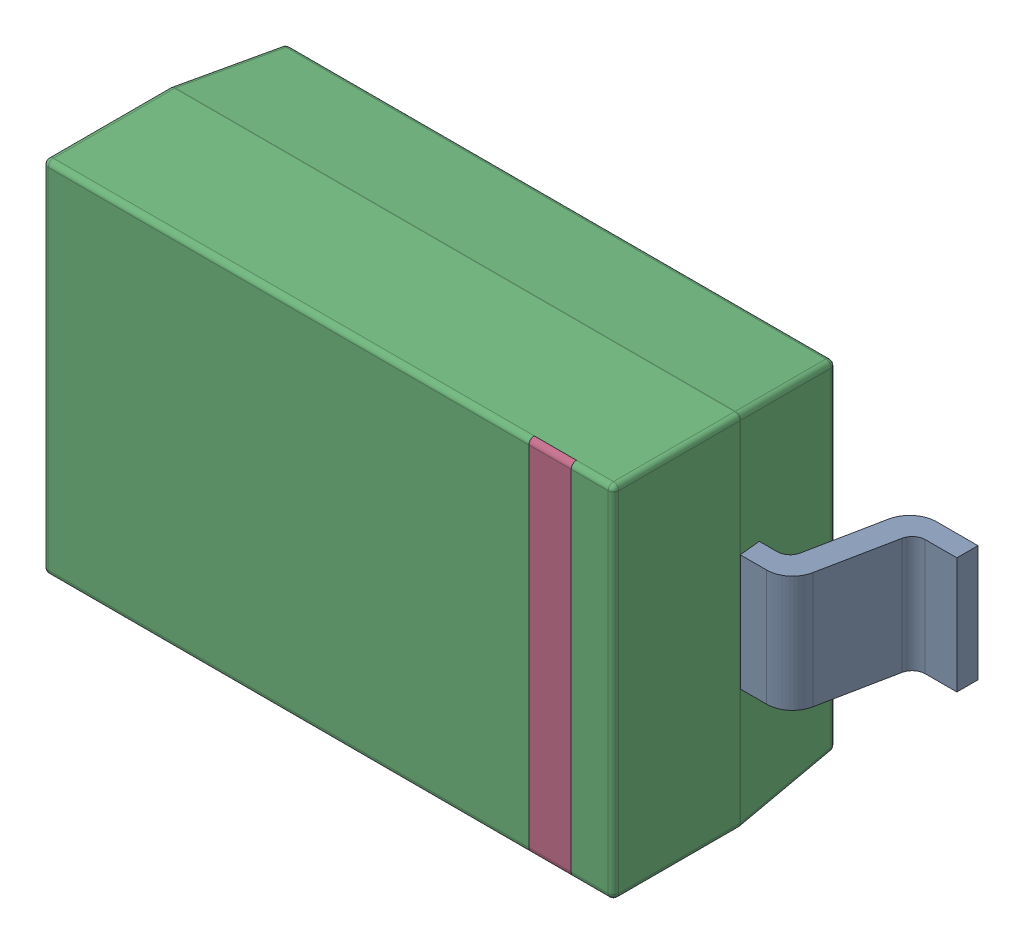
SolidWorks assembly D4, configuration Default. Lengths in mm.
Overall size (3.75 1.71 1.2).
5 component instances, 4 part files, 0 mates.
Components (placement in the parent):
- sod123_v4-1: sod123_v4 [Default] at (27.3899 11.0899 0) x (-1 0 0) z (0 0 1) size (3.75 1.71 1.2)
  - pin-1: pin [Default] at (-0.675 -0.875 0) x (0 -1 0) z (0 0 1) size (0.55 0.55 0.6)
  - pin(Mirror)-1: pin(Mirror) [Default] at (0.675 -0.875 0) x (0 -1 0) z (0 0 -1) size (0.55 0.55 0.6)
  - icbody-1: icbody [Default] at origin size (2.71 1.71 1.11)
  - Component5-1: Component5 [Default] at origin size (0.2 1.7 0.02)
